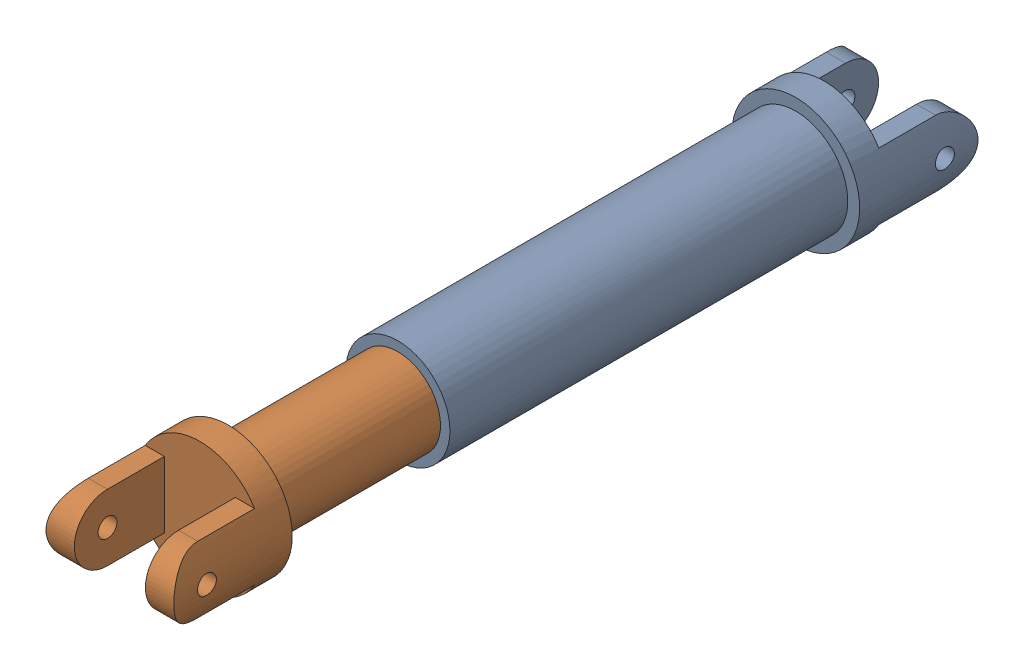
SolidWorks assembly Slip Yoke_Rear, configuration Default. Lengths in mm.
Overall size (13.5 13.5 84.9).
2 component instances, 2 part files, 3 mates.
Components (placement in the parent):
- U Joint A - Outer Yoke_Rear-1: U Joint A - Outer Yoke_Rear [Default] at (19.5991 29.2682 47.9142) size (13.5 13.5 54.5)
- U Joint B - Inner Yoke_Rear-1: U Joint B - Inner Yoke_Rear [Default] at (19.5991 29.2682 63.8158) x (-1 0 0) z (0 0 -1) size (13.5 13.5 58.5)
Mates (geometry in assembly coordinates):
- Concentric1: concentric: cylinder of U Joint A - Outer Yoke_Rear-1 through (19.5991 29.2682 26.9142) axis (0 0 1) radius 4.5; cylinder of U Joint B - Inner Yoke_Rear-1 through (19.5991 29.2682 40.8158) axis (0 0 1) radius 4.5
- Coincident2: coincident: plane of U Joint A - Outer Yoke_Rear-1 through (20.0991 25.2961 26.9142) normal (0 1 0); plane of U Joint B - Inner Yoke_Rear-1 through (20.0991 25.2961 86.8158) normal (0 -1 0)
- LimitDistance2: limit distance = 13.9016 mm: plane of U Joint A - Outer Yoke_Rear-1 through (19.5991 29.2682 26.9142) normal (0 0 1); plane of U Joint B - Inner Yoke_Rear-1 through (19.5991 29.2682 40.8158) normal (0 0 -1)
